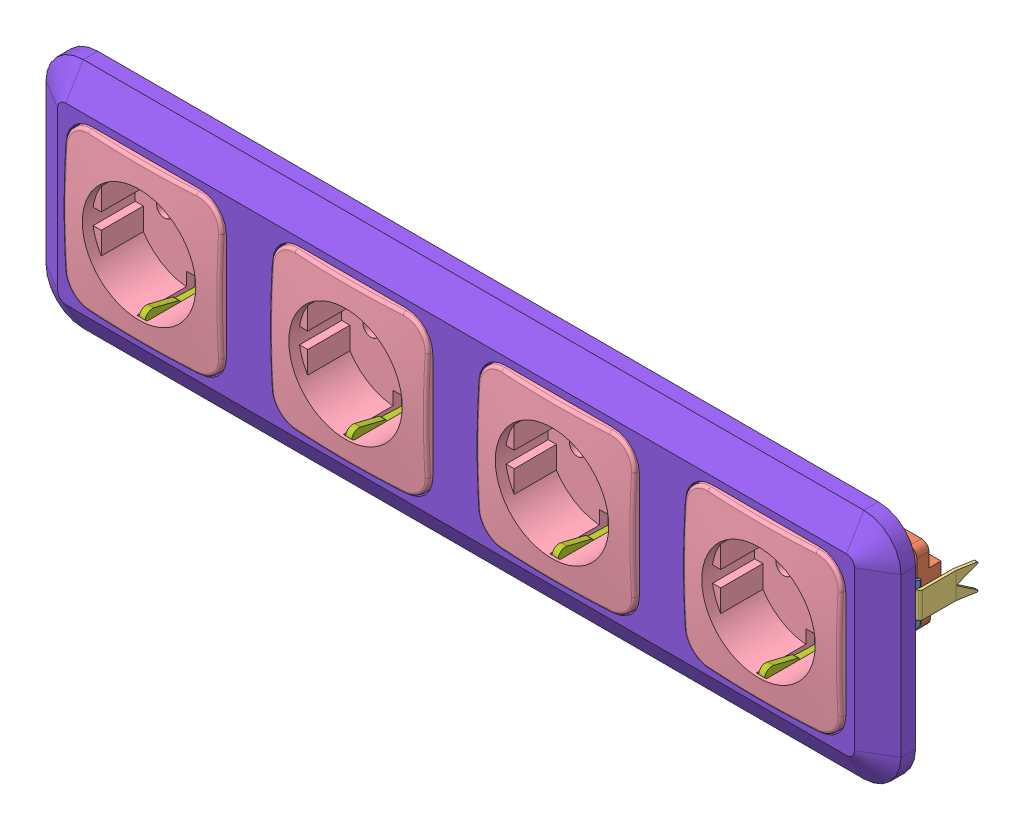
SolidWorks assembly Steckdose_4er, configuration Standard. Lengths in mm.
Overall size (294 80 49.07).
37 component instances, 8 part files, 12 mates.
Components (placement in the parent):
- Steckdose-1: Steckdose [Standard] at (57.8004 112.8398 -124.7318) x (1 0 0) z (0 -1 0) size (71 49.07 71)
  - Montageplatte.02-1: Montageplatte.02 [Standard] at (-76.9981 11 50.9191) x (1 0 0) z (0 1 0) size (71 71 18.97)
  - Halter-1: Halter [Standard] at (-76.9981 11 50.9191) x (1 0 0) z (0 1 0) size (45.97 31.9 15.37)
  - Kralle.04-1: Kralle.04 [Standard] at (-74.3121 12.4168 50.9191) x (0.996195 -0.087156 0) z (0.087156 0.996195 0) size (8.78 9 23.36)
  - Kralle.04-2: Kralle.04 [Standard] at (74.3121 12.4168 -50.9191) x (-0.996195 -0.087156 0) z (-0.087156 0.996195 0) size (8.78 9 23.36)
  - Buchse-1: Buchse [Standard] at (-76.9981 11 50.9191) x (1 0 0) z (0 1 0) size (64.03 64.03 27)
  - Stromklemme_1.02-1: Stromklemme_1.02 [Standard] at (-76.9981 11 50.7921) x (1 0 0) z (0 1 0) size (8.38 19.82 12.51)
  - Stromklemme_2.02-1: Stromklemme_2.02 [Standard] at (-76.9981 11 50.7921) x (1 0 0) z (0 1 0) size (8.38 19.82 12.51)
  - Erdleiter-1: Erdleiter [Standard] at (-76.9981 11 50.9191) x (1 0 0) z (0 1 0) size (7.24 44.01 27.12)
- Steckdose-2: Steckdose [Standard] at (128.8004 112.8398 -124.7318) x (1 0 0) z (0 -1 0) size (71 49.07 71)
  - Montageplatte.02-1: Montageplatte.02 [Standard] at (-76.9981 11 50.9191) x (1 0 0) z (0 1 0) size (71 71 18.97)
  - Halter-1: Halter [Standard] at (-76.9981 11 50.9191) x (1 0 0) z (0 1 0) size (45.97 31.9 15.37)
  - Kralle.04-1: Kralle.04 [Standard] at (-74.3121 12.4168 50.9191) x (0.996195 -0.087156 0) z (0.087156 0.996195 0) size (8.78 9 23.36)
  - Kralle.04-2: Kralle.04 [Standard] at (74.3121 12.4168 -50.9191) x (-0.996195 -0.087156 0) z (-0.087156 0.996195 0) size (8.78 9 23.36)
  - Buchse-1: Buchse [Standard] at (-76.9981 11 50.9191) x (1 0 0) z (0 1 0) size (64.03 64.03 27)
  - Stromklemme_1.02-1: Stromklemme_1.02 [Standard] at (-76.9981 11 50.7921) x (1 0 0) z (0 1 0) size (8.38 19.82 12.51)
  - Stromklemme_2.02-1: Stromklemme_2.02 [Standard] at (-76.9981 11 50.7921) x (1 0 0) z (0 1 0) size (8.38 19.82 12.51)
  - Erdleiter-1: Erdleiter [Standard] at (-76.9981 11 50.9191) x (1 0 0) z (0 1 0) size (7.24 44.01 27.12)
- Wandplatte-1: Wandplatte [4er] at (17.3004 72.8398 -113.7318) size (294 80 11)
- Steckdose-3: Steckdose [Standard] at (270.8004 112.8398 -124.7318) x (1 0 0) z (0 -1 0) size (71 49.07 71)
  - Montageplatte.02-1: Montageplatte.02 [Standard] at (-76.9981 11 50.9191) x (1 0 0) z (0 1 0) size (71 71 18.97)
  - Halter-1: Halter [Standard] at (-76.9981 11 50.9191) x (1 0 0) z (0 1 0) size (45.97 31.9 15.37)
  - Kralle.04-1: Kralle.04 [Standard] at (-74.3121 12.4168 50.9191) x (0.996195 -0.087156 0) z (0.087156 0.996195 0) size (8.78 9 23.36)
  - Kralle.04-2: Kralle.04 [Standard] at (74.3121 12.4168 -50.9191) x (-0.996195 -0.087156 0) z (-0.087156 0.996195 0) size (8.78 9 23.36)
  - Buchse-1: Buchse [Standard] at (-76.9981 11 50.9191) x (1 0 0) z (0 1 0) size (64.03 64.03 27)
  - Stromklemme_1.02-1: Stromklemme_1.02 [Standard] at (-76.9981 11 50.7921) x (1 0 0) z (0 1 0) size (8.38 19.82 12.51)
  - Stromklemme_2.02-1: Stromklemme_2.02 [Standard] at (-76.9981 11 50.7921) x (1 0 0) z (0 1 0) size (8.38 19.82 12.51)
  - Erdleiter-1: Erdleiter [Standard] at (-76.9981 11 50.9191) x (1 0 0) z (0 1 0) size (7.24 44.01 27.12)
- Steckdose-4: Steckdose [Standard] at (199.8004 112.8398 -124.7318) x (1 0 0) z (0 -1 0) size (71 49.07 71)
  - Montageplatte.02-1: Montageplatte.02 [Standard] at (-76.9981 11 50.9191) x (1 0 0) z (0 1 0) size (71 71 18.97)
  - Halter-1: Halter [Standard] at (-76.9981 11 50.9191) x (1 0 0) z (0 1 0) size (45.97 31.9 15.37)
  - Kralle.04-1: Kralle.04 [Standard] at (-74.3121 12.4168 50.9191) x (0.996195 -0.087156 0) z (0.087156 0.996195 0) size (8.78 9 23.36)
  - Kralle.04-2: Kralle.04 [Standard] at (74.3121 12.4168 -50.9191) x (-0.996195 -0.087156 0) z (-0.087156 0.996195 0) size (8.78 9 23.36)
  - Buchse-1: Buchse [Standard] at (-76.9981 11 50.9191) x (1 0 0) z (0 1 0) size (64.03 64.03 27)
  - Stromklemme_1.02-1: Stromklemme_1.02 [Standard] at (-76.9981 11 50.7921) x (1 0 0) z (0 1 0) size (8.38 19.82 12.51)
  - Stromklemme_2.02-1: Stromklemme_2.02 [Standard] at (-76.9981 11 50.7921) x (1 0 0) z (0 1 0) size (8.38 19.82 12.51)
  - Erdleiter-1: Erdleiter [Standard] at (-76.9981 11 50.9191) x (1 0 0) z (0 1 0) size (7.24 44.01 27.12)
Mates (geometry in assembly coordinates):
- Deckungsgleich1: coincident anti-aligned: plane of Steckdose-2/Buchse-1 through (128.8004 86.3398 -119.7318) normal (0 0 -1); plane of Wandplatte-1 through (110.3004 94.3398 -119.7318) normal (0 0 1)
- Deckungsgleich2: coincident anti-aligned: plane of Steckdose-1/Buchse-1 through (57.8004 86.3398 -119.7318) normal (0 0 -1); plane of Wandplatte-1 through (39.3004 94.3398 -119.7318) normal (0 0 1)
- Abstand1: distance = 0.5 mm anti-aligned: plane of Wandplatte-1 through (39.3004 140.3398 -119.7318) normal (0 -1 0); plane of Steckdose-1/Buchse-1 through (39.3004 139.8398 -119.7318) normal (0 1 0)
- Abstand2: distance = 0.5 mm anti-aligned: plane of Steckdose-1/Buchse-1 through (30.8004 94.3398 -119.7318) normal (-1 0 0); plane of Wandplatte-1 through (30.3004 131.3398 -119.7318) normal (1 0 0)
- Abstand3: distance = 0.5 mm anti-aligned: plane of Steckdose-2/Buchse-1 through (110.3004 139.8398 -119.7318) normal (0 1 0); plane of Wandplatte-1 through (110.3004 140.3398 -119.7318) normal (0 -1 0)
- Abstand4: distance = 0.5 mm anti-aligned: plane of Steckdose-2/Buchse-1 through (101.8004 94.3398 -119.7318) normal (-1 0 0); plane of Wandplatte-1 through (101.3004 131.3398 -119.7318) normal (1 0 0)
- Deckungsgleich3: coincident anti-aligned: plane of Wandplatte-1 through (181.3004 94.3398 -119.7318) normal (0 0 1); plane of Steckdose-4/Buchse-1 through (199.8004 86.3398 -119.7318) normal (0 0 -1)
- Deckungsgleich4: coincident anti-aligned: plane of Wandplatte-1 through (252.3004 94.3398 -119.7318) normal (0 0 1); plane of Steckdose-3/Buchse-1 through (270.8004 86.3398 -119.7318) normal (0 0 -1)
- Abstand5: distance = 0.5 mm anti-aligned: plane of Steckdose-4/Buchse-1 through (218.3004 85.8398 -119.7318) normal (0 -1 0); plane of Wandplatte-1 through (181.3004 85.3398 -119.7318) normal (0 1 0)
- Abstand6: distance = 0.5 mm anti-aligned: plane of Wandplatte-1 through (252.3004 85.3398 -119.7318) normal (0 1 0); plane of Steckdose-3/Buchse-1 through (289.3004 85.8398 -119.7318) normal (0 -1 0)
- Abstand7: distance = 0.5 mm anti-aligned: plane of Steckdose-3/Buchse-1 through (297.8004 131.3398 -119.7318) normal (1 0 0); plane of Wandplatte-1 through (298.3004 131.3398 -119.7318) normal (-1 0 0)
- Abstand8: distance = 0.5 mm anti-aligned: plane of Wandplatte-1 through (227.3004 131.3398 -119.7318) normal (-1 0 0); plane of Steckdose-4/Buchse-1 through (226.8004 131.3398 -119.7318) normal (1 0 0)
